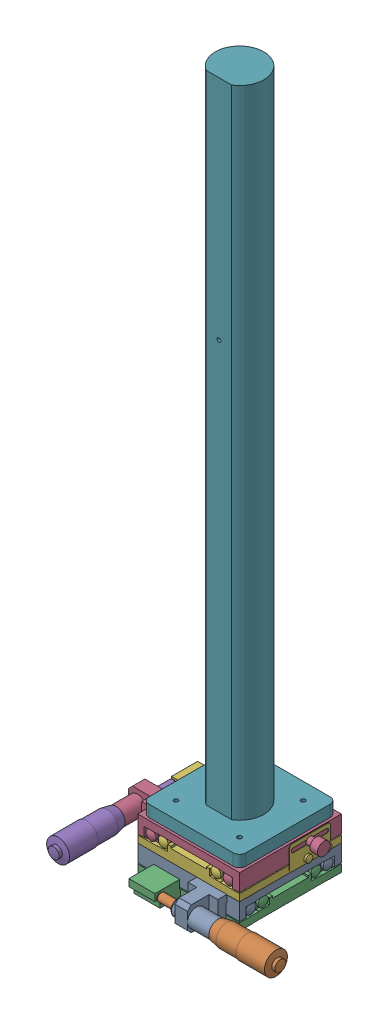
SolidWorks assembly d_shaft assembled, configuration Default. Lengths in mm.
Overall size (155.6 549.16 140.9).
3 component instances, 2 part files, 0 mates.
Components (placement in the parent):
- B11-80CZ.step_1-1: B11-80CZ.step_1 [Default] at (24.4701 -2.1391 -38.5314) x (1 0 0) z (0 1 0) size (130.2 117.3 20.22)
- B11-80CZ.step_1-2: B11-80CZ.step_1 [Default] at (24.4701 17.6609 -38.5314) x (0 0 1) z (0 1 0) size (130.2 117.3 20.22)
- d_shaft-1: d_shaft [Default] at (24.4701 46.8049 -38.5314) size (76.2 509.14 76.2)
